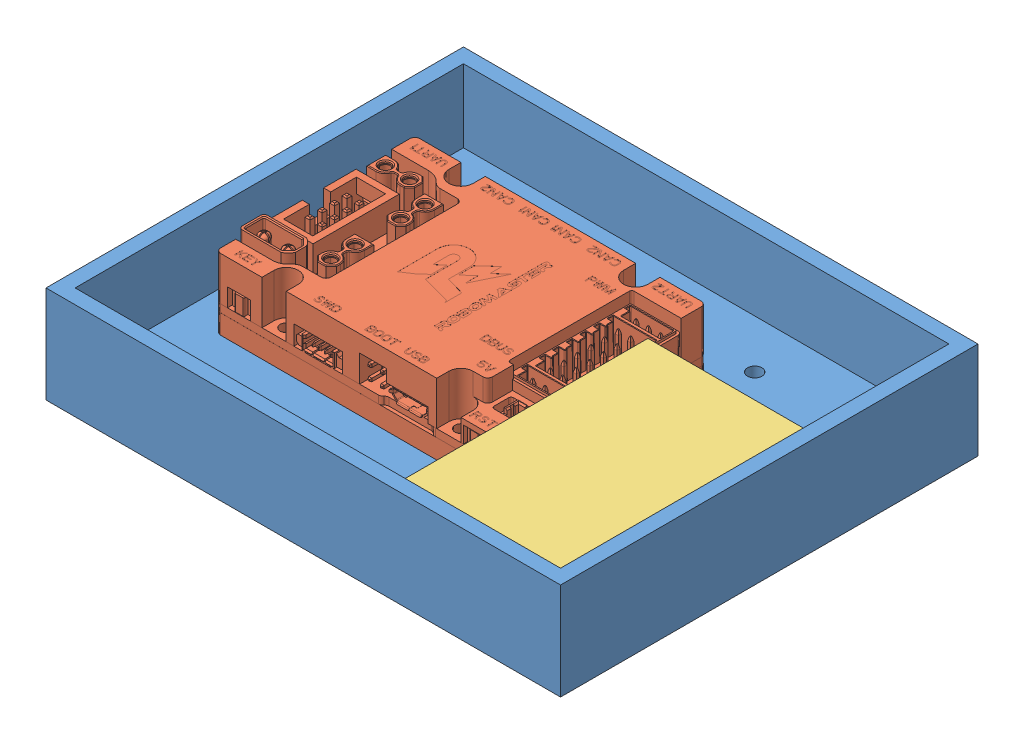
SolidWorks assembly 控制盒装配体, configuration 默认. Lengths in mm.
Overall size (106 21.3 86).
3 component instances, 3 part files, 6 mates.
Components (placement in the parent):
- 控制盒1.0-1: 控制盒1.0 [默认] at (4.0041 -21.9055 106) size (106 20 86)
- DJI_C-1: DJI_C [默认] at (-30.2256 3.6945 128.5605) x (0 0 1) z (0 1 0) size (47 60.33 16.3)
- 匿名透传（简）-1: 匿名透传（简） [默认] at (22.0041 -16.9055 96) x (0 0 1) z (-1 0 0) size (50 15 32)
Mates (geometry in assembly coordinates):
- 重合1: coincident anti-aligned: plane of 控制盒1.0-1 through (4.0041 -16.9055 106) normal (0 1 0); plane of DJI_C-1 through (-8.5458 -16.9055 103.96) normal (0 -1 0)
- 同心1: concentric aligned: circle of 控制盒1.0-1; circle of DJI_C-1
- 同心2: concentric aligned: circle of 控制盒1.0-1; circle of DJI_C-1
- 重合2: coincident anti-aligned: plane of 控制盒1.0-1 through (4.0041 -16.9055 106) normal (0 1 0); plane of 匿名透传（简）-1 through (22.0041 -16.9055 96) normal (0 -1 0)
- 重合3: coincident anti-aligned: plane of 控制盒1.0-1 through (4.0041 -21.9055 146) normal (0 0 -1); plane of 匿名透传（简）-1 through (22.0041 -1.9055 146) normal (0 0 1)
- 重合4: coincident anti-aligned: plane of 控制盒1.0-1 through (54.0041 -21.9055 106) normal (-1 0 0); plane of 匿名透传（简）-1 through (54.0041 -1.9055 146) normal (1 0 0)
